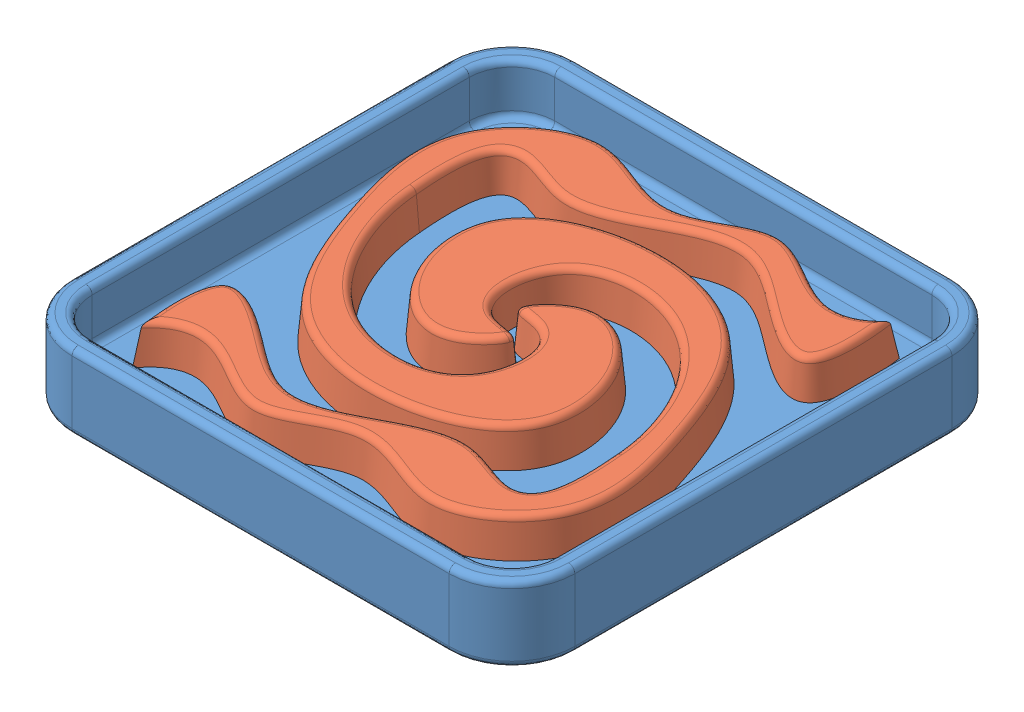
SolidWorks assembly Assem7, configuration Default. Lengths in mm.
Overall size (40 6 40).
3 component instances, 2 part files, 3 mates.
Components (placement in the parent):
- Tile-1: Tile [Default] at (13.3879 15.9902 32.7976) size (40 6 40)
- VortexHalf-1: VortexHalf [Default] at (13.4215 17.9902 32.3976) size (35 3.6 35.15)
- VortexHalf-2: VortexHalf [Default] at (12.6433 17.9902 31.8677) x (-1 0 0) z (0 0 -1) size (35 3.6 35.15)
Mates (geometry in assembly coordinates):
- Coincident1: coincident anti-aligned: plane of Tile-1 through (-1.6121 17.9902 47.7976) normal (0 1 0); plane of VortexHalf-1 through (10.8357 17.9902 45.531) normal (0 -1 0)
- Coincident2: coincident anti-aligned: line of Tile-1 through (28.3879 17.9902 14.8976) axis (-1 0 0); line of VortexHalf-1 through (-4.0785 17.9902 14.8976) axis (1 0 0)
- Coincident3: coincident anti-aligned: plane of Tile-1 through (-1.6121 17.9902 47.7976) normal (0 1 0); plane of VortexHalf-2 through (15.2291 17.9902 18.7344) normal (0 -1 0)
